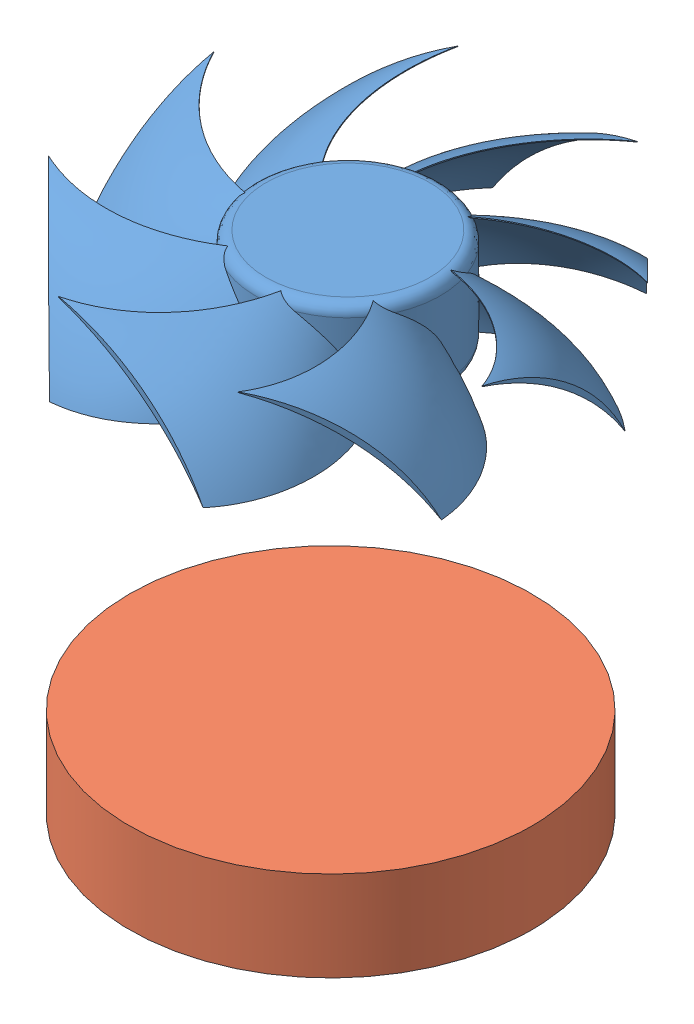
SolidWorks assembly Assem1, configuration Varsayılan. Lengths in mm.
Overall size (426.2 514.67 409.96).
2 component instances, 2 part files, 0 mates.
Components (placement in the parent):
- prop2-1: prop2 [Varsayılan(1)] at (-10.6876 -8.1468 80.2819) size (401.41 106.99 401.41)
- surface-1: surface [Varsayılan] at (-46.1871 -330.5744 61.0312) x (1 0 0) z (0 -1 0) size (380 380 85)
